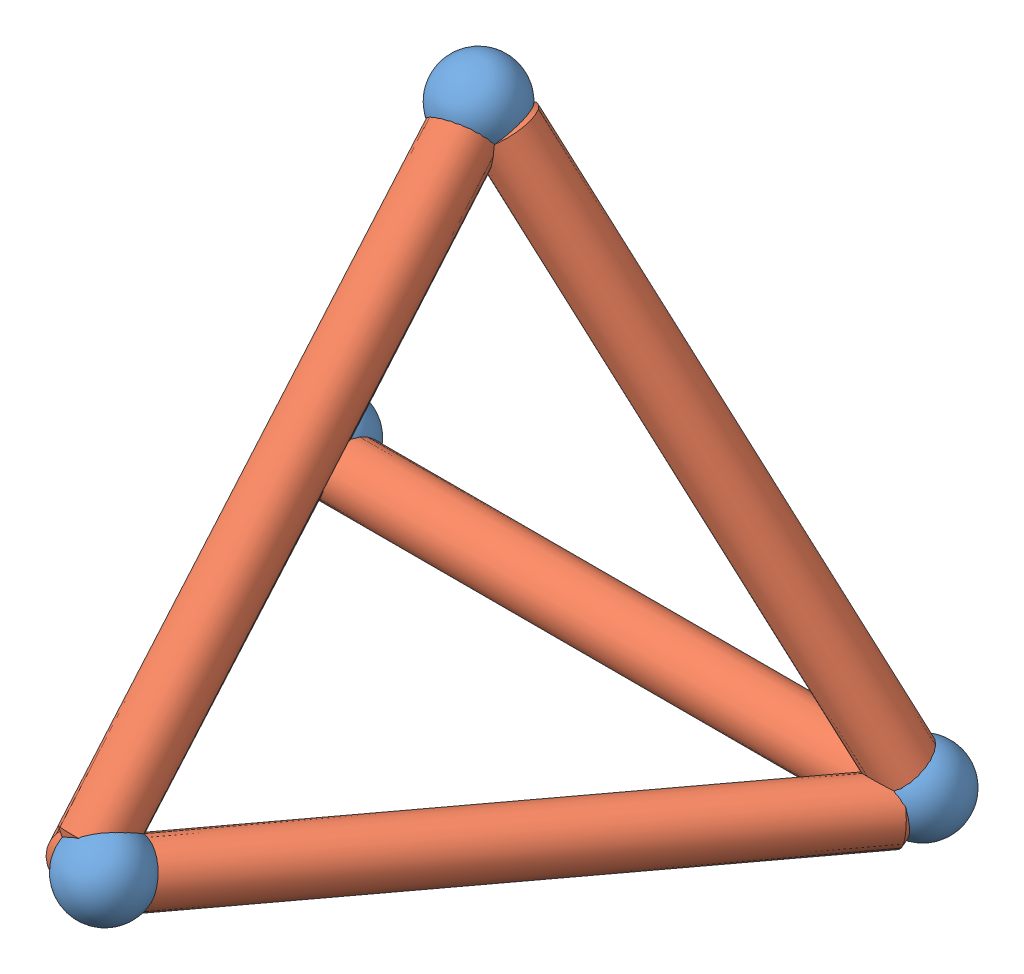
SolidWorks assembly Ensamblaje2, configuration Predeterminado. Lengths in mm.
Overall size (440.78 379.81 395.3).
10 component instances, 2 part files, 8 mates.
Components (placement in the parent):
- parte 3-1: parte 3 [Predeterminado] at (-68.6706 20.4802 51.071) size (50 50 50)
- parte 4-7: parte 4 [Predeterminado] at (-392.2398 -16.8105 52.601) size (400 36.36 36.36)
- parte 4-8: parte 4 [Predeterminado] at (-431.1788 -10.3133 121.0948) x (0.5 0.081782 0.862155) z (-0.862155 -0.047006 0.504459) size (400 36.36 36.36)
- parte 4-9: parte 4 [Predeterminado] at (-234.6767 10.1414 328.234) x (0.5 -0.081782 -0.862155) z (0.765459 -0.423897 0.484132) size (400 36.36 36.36)
- parte 4-11: parte 4 [Predeterminado] at (-237.8401 256.2239 120.7523) x (0.5 -0.840109 -0.21028) z (0.188134 -0.131643 0.973281) size (400 36.36 36.36)
- parte 4-12: parte 4 [Predeterminado] at (-425.7893 52.9551 70.3234) x (0.5 0.840109 0.21028) z (-0.240686 -0.098443 0.965598) size (400 36.36 36.36)
- parte 4-13: parte 4 [Predeterminado] at (-265.8445 79.9823 342.3786) x (0 0.758326 -0.651875) z (0.651875 0.494334 0.575058) size (400 36.36 36.36)
- parte 3-6: parte 3 [Predeterminado] at (-265.5665 344.5886 137.5686) size (50 50 50)
- parte 3-7: parte 3 [Predeterminado] at (-453.0779 19.5512 46.6031) size (50 50 50)
- parte 3-8: parte 3 [Predeterminado] at (-253.2777 49.9572 388.3335) size (50 50 50)
Mates (geometry in assembly coordinates):
- Coincidente2: coincident: point of parte 4-7; point of parte 4-9
- Coincidente3: coincident: point of parte 4-8; point of parte 4-9
- Coincidente6: coincident: point of parte 4-7; point of parte 4-8
- Coincidente8: coincident: point of parte 4-9; point of parte 4-11
- Coincidente9: coincident: point of parte 4-11; point of parte 4-12
- Coincidente10: coincident: point of parte 4-8; point of parte 4-12
- Coincidente11: coincident: point of parte 4-11; point of parte 4-13
- Coincidente12: coincident: point of parte 4-9; point of parte 4-13
